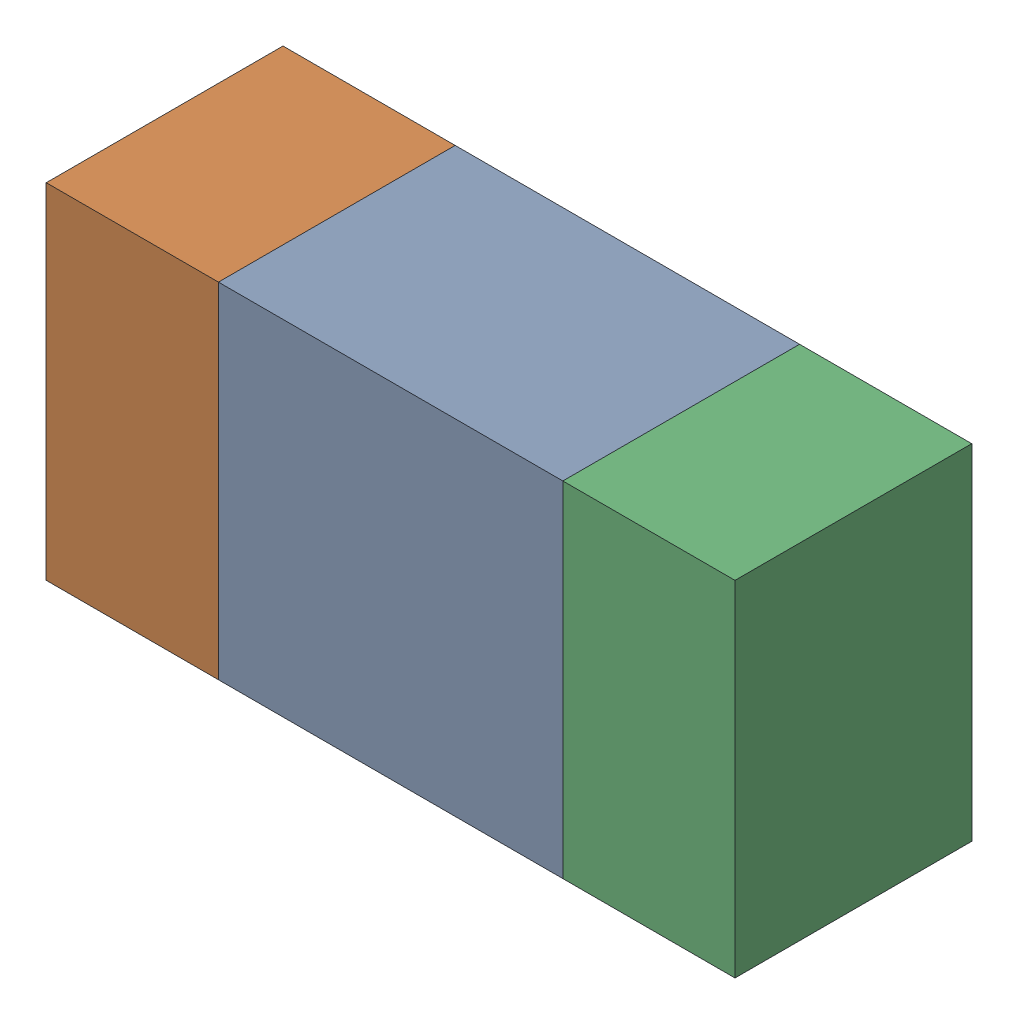
SolidWorks assembly R41, configuration ﾃﾞﾌｫﾙﾄ. Lengths in mm.
Overall size (1.6 0.8 0.55).
6 component instances, 2 part files, 0 mates.
Components (placement in the parent):
- 689261648-1: 689261648 [ﾃﾞﾌｫﾙﾄ] at (59 22.8001 -1.7503) size (0.8 0.8 0.55)
  - Extruded_33-1: Extruded_33 [ﾃﾞﾌｫﾙﾄ] at origin size (0.8 0.8 0.55)
- 689261512-1: 689261512 [ﾃﾞﾌｫﾙﾄ] at (58.3999 22.8001 -1.7503) size (0.4 0.8 0.55)
  - Extruded_32-1: Extruded_32 [ﾃﾞﾌｫﾙﾄ] at origin size (0.4 0.8 0.55)
- 689261512-2: 689261512 [ﾃﾞﾌｫﾙﾄ] at (59.5999 22.8001 -1.7503) size (0.4 0.8 0.55)
  - Extruded_32-1: Extruded_32 [ﾃﾞﾌｫﾙﾄ] at origin size (0.4 0.8 0.55)
